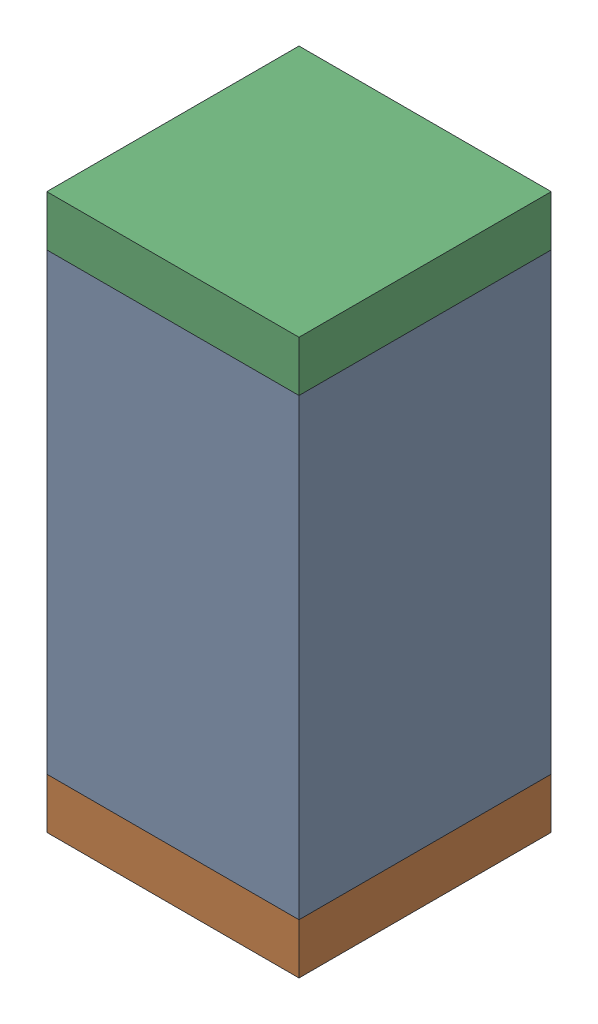
SolidWorks assembly C25, configuration Default. Lengths in mm.
Overall size (0.5 1.1 0.5).
6 component instances, 2 part files, 0 mates.
Components (placement in the parent):
- 791586336-1: 791586336 [Default] at (113.05 26.1 0) size (0.5 0.9 0.5)
  - Extruded_8-1: Extruded_8 [Default] at origin size (0.5 0.9 0.5)
- 810157360-1: 810157360 [Default] at (113.05 25.6 0) size (0.5 0.1 0.5)
  - Extruded_9-1: Extruded_9 [Default] at origin size (0.5 0.1 0.5)
- 810157360-2: 810157360 [Default] at (113.05 26.6 0) size (0.5 0.1 0.5)
  - Extruded_9-1: Extruded_9 [Default] at origin size (0.5 0.1 0.5)
